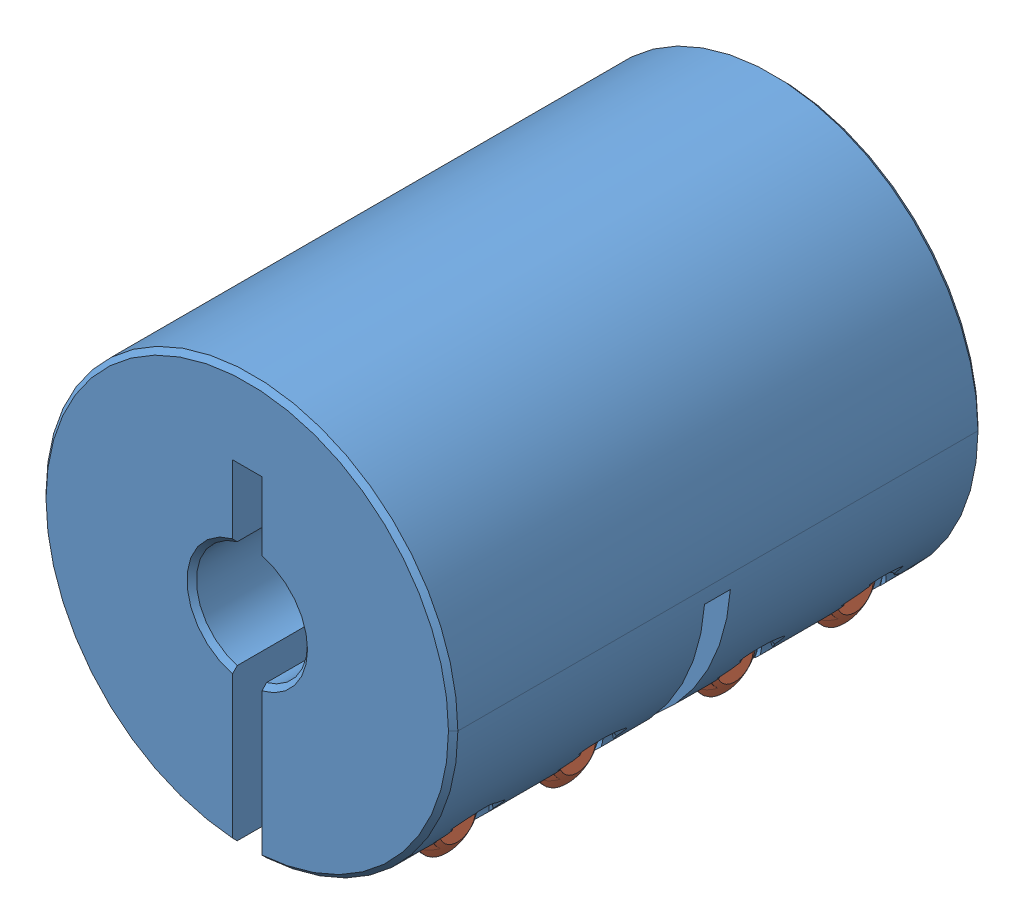
SolidWorks assembly 625100 assembly.STEP, configuration Default. Lengths in mm.
Overall size (22.23 22.2 28.57).
5 component instances, 2 part files, 0 mates.
Components (placement in the parent):
- 625100.STEP-1: 625100.STEP [Default] at (-36.0907 -0.3474 4.9835) size (22.23 22.2 28.57)
- 632112_90128A121.STEP-1: 632112_90128A121.STEP [Default] at (-1.3244 -7.8756 30.0025) x (0 0 -1) z (1 0 0) size (5.61 5.61 14.62)
- 632112_90128A121.STEP-2: 632112_90128A121.STEP [Default] at (-1.3244 -7.8756 23.5255) x (0 0 -1) z (1 0 0) size (5.61 5.61 14.62)
- 632112_90128A121.STEP-3: 632112_90128A121.STEP [Default] at (-1.3244 -7.8756 15.0165) x (0 0 -1) z (1 0 0) size (5.61 5.61 14.62)
- 632112_90128A121.STEP-4: 632112_90128A121.STEP [Default] at (-1.3244 -7.8756 8.5395) x (0 0 -1) z (1 0 0) size (5.61 5.61 14.62)
